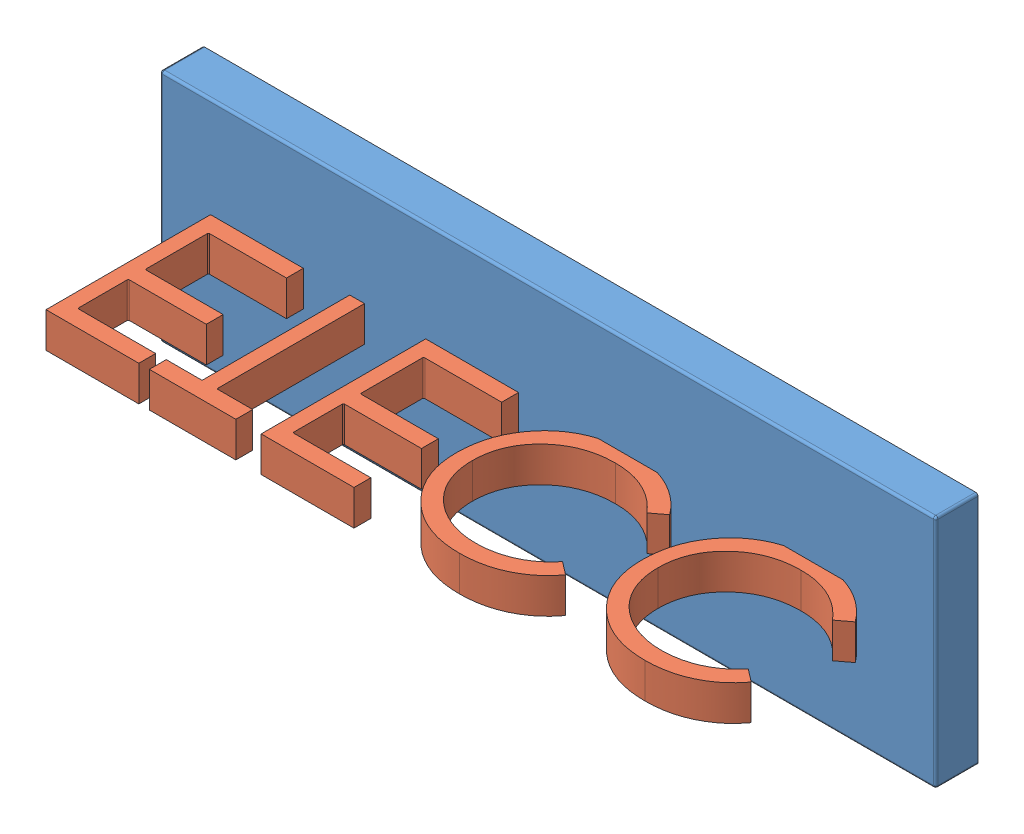
SolidWorks assembly Assemblage1, configuration Défaut. Lengths in mm.
Overall size (330 100 89.79).
2 component instances, 2 part files, 4 mates.
Components (placement in the parent):
- plateau-1: plateau [Défaut] at (-45.9734 -34.3686 321) size (330 100 18)
- Lettres-1: Lettres [Défaut] at (-177.25 4.2758 339) x (1 0 0) z (0 -1 0) size (287.18 71.79 15)
Mates (geometry in assembly coordinates):
- Coïncidente1: coincident anti-aligned: plane of plateau-1 through (-45.9734 -34.3686 339) normal (0 0 1); plane of Lettres-1 through (-27.6394 4.2758 339) normal (0 0 -1)
- Parallèle1: parallel aligned: plane of plateau-1 through (-189.7756 -53.2242 339) normal (0 -1 0); plane of Lettres-1 through (-177.25 -10.7242 339) normal (0 -1 0)
- Distance1: distance = 42.5 mm aligned: plane of Lettres-1 through (-177.25 -10.7242 339) normal (0 -1 0); plane of plateau-1 through (-189.7756 -53.2242 339) normal (0 -1 0)
- Distance4: distance = 21.5 mm aligned: plane of plateau-1 through (-189.7756 46.7758 339) normal (-1 0 0); plane of Lettres-1 through (-168.2756 -10.7242 339) normal (-1 0 0)
